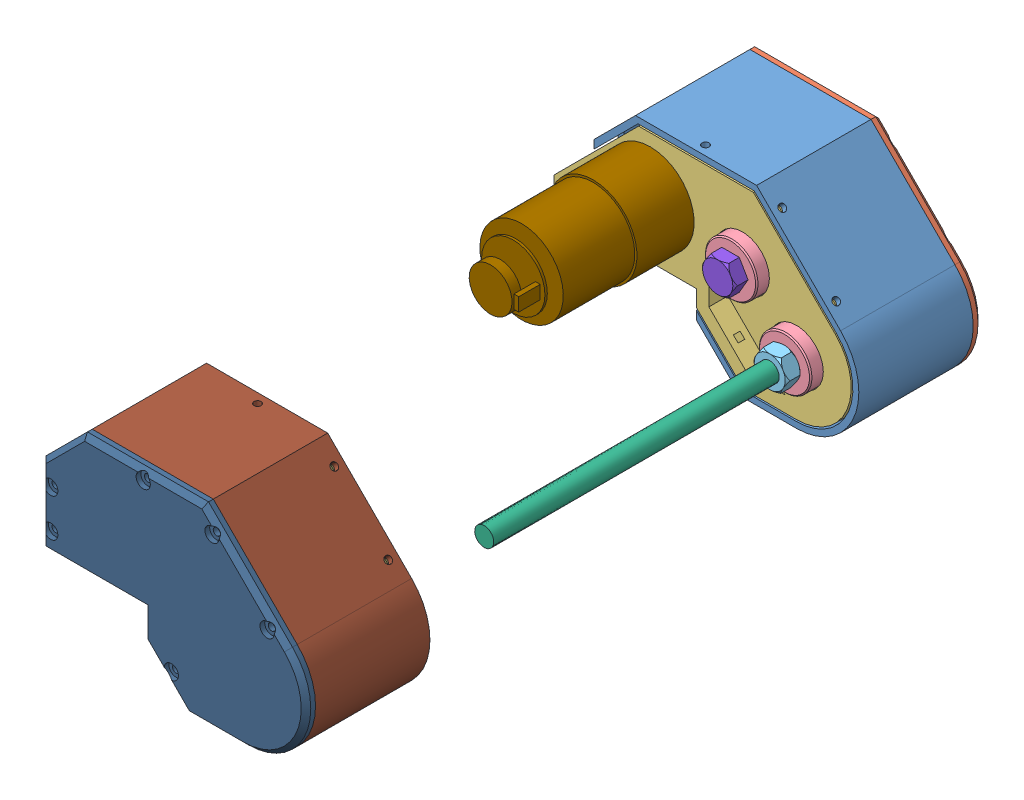
SolidWorks assembly 1_support_assembly, configuration Valor predeterminado. Lengths in mm.
Overall size (127.9 79.95 283.98).
20 component instances, 14 part files, 39 mates.
Components (placement in the parent):
- motorPlate-case-1: motorPlate-case [Valor predeterminado] at (-65.1774 -10.6604 87.1) size (111.1 79.95 48)
- motorPlate-lid-1: motorPlate-lid [Valor predeterminado] at (-65.1774 -10.6604 87.1) size (111.1 79.95 4)
- motorPlate-1: motorPlate [Valor predeterminado] at (-65.1774 -10.6604 127.1) size (124.7 73.55 8)
- bearing-1: bearing [Valor predeterminado] at (16.5226 -14.2604 122.1) size (22 22 7)
- nut-1: nut [Valor predeterminado] at (16.5226 -14.2604 115.9) size (16.51 13 6.2)
- threaded_rod-2: threaded_rod [Valor predeterminado] at (16.5226 -14.2604 90.1) x (0.592807 -0.805345 0) z (0 0 1) size (8 8 176)
- rod_gear_big_simple-1: rod_gear_big_simple [Valor predeterminado] at (16.5226 -14.2604 105.3824) x (0.982602 0.185725 0) z (0 0 -1) size (40.8 40.8 10)
- nut-2: nut [Valor predeterminado] at (16.5226 -14.2604 105.3824) size (16.51 13 6.2)
- nut-4: nut [Valor predeterminado] at (16.5226 -14.2604 140.1) x (0.999879 -0.015551 0) z (0 0 1) size (16.51 13 6.2)
- nut-5: nut [Valor predeterminado] at (16.5226 -14.2604 93.6824) size (16.51 13 6.2)
- bearing-2: bearing [Valor predeterminado] at (-6.1048 8.367 133.1) size (22 22 7)
- bearing-3: bearing [Valor predeterminado] at (-6.1048 8.367 122.1) size (22 22 7)
- bearing-4: bearing [Valor predeterminado] at (16.5226 -14.2604 133.1) size (22 22 7)
- bolt-1: bolt [Valor predeterminado] at (-6.1048 8.367 145.5) x (1 0 0) z (0 0 -1) size (16.13 12.7 55.4)
- motor_pololu-1: motor_pololu [Valor predeterminado] at (-44.7934 12.8206 135.1) x (0 -1 0) z (0 0 1) size (36.8 36.8 89)
- motorPlate-board_lid-1: motorPlate-board_lid [Valor predeterminado] at (-65.1774 -10.6604 363.0779) size (111.1 79.95 4)
- motorPlate-board_case-2: motorPlate-board_case [Valor predeterminado] at (-65.1774 -10.6604 267.0779) size (111.1 79.95 48)
- motorPlate-board-1: motorPlate-board [Valor predeterminado] at (-65.1774 -10.6604 315.0779) size (124.7 73.55 8)
- motor_gear_simple-1: motor_gear_simple [Valor predeterminado] at (-37.7934 12.8206 108.3824) x (0.999999 -0.00117 0) z (0 0 1) size (30 30 17)
- reduction_gear_simple-1: reduction_gear_simple [Valor predeterminado] at (-6.1048 8.367 108.3824) x (0.996288 -0.086078 0) z (0 0 1) size (40.8 40.8 23)
Mates (geometry in assembly coordinates):
- Coincidente5: coincident aligned: line of motorPlate-case-1 through (-0.174 39.4886 87.1) axis (-1 0 0); line of motorPlate-lid-1 through (-0.174 39.4886 87.1) axis (-1 0 0)
- Coincidente6: coincident aligned: line of motorPlate-case-1 through (-68.3774 22.107 87.1) axis (0 -1 0); line of motorPlate-lid-1 through (-68.3774 22.107 87.1) axis (0 -1 0)
- Concêntrico1: concentric aligned: circle of motorPlate-case-1; circle of motorPlate-1
- Coincidente8: coincident anti-aligned: plane of motorPlate-1 through (16.5226 -14.2604 129.1) normal (0 0 -1); plane of bearing-1 through (16.5226 -14.2604 129.1) normal (0 0 1)
- Concêntrico7: concentric anti-aligned: circle of motorPlate-1; circle of bearing-1
- Coincidente9: coincident anti-aligned: plane of bearing-1 through (16.5226 -14.2604 122.1) normal (0 0 -1); plane of nut-1 through (16.5226 -14.2604 122.1) normal (0 0 1)
- Concêntrico8: concentric aligned: circle of bearing-1; circle of nut-1
- Concêntrico9: concentric anti-aligned: circle of threaded_rod-2; circle of rod_gear_big_simple-1
- Coincidente12: coincident anti-aligned: plane of rod_gear_big_simple-1 through (16.5226 -14.2604 105.3824) normal (0 0 1); plane of nut-2 through (16.5226 -14.2604 105.3824) normal (0 0 -1)
- Concêntrico10: concentric anti-aligned: circle of rod_gear_big_simple-1; circle of nut-2
- Concêntrico11: concentric aligned: circle of threaded_rod-2; circle of nut-2
- Coincidente14: coincident anti-aligned: plane of rod_gear_big_simple-1 through (16.5226 -14.2604 99.8824) normal (0 0 -1); plane of nut-5 through (16.5226 -14.2604 99.8824) normal (0 0 1)
- Concêntrico12: concentric anti-aligned: circle of rod_gear_big_simple-1; circle of nut-5
- Coincidente15: coincident anti-aligned: plane of motorPlate-1 through (-6.1048 8.367 133.1) normal (0 0 1); plane of bearing-2 through (-6.1048 8.367 133.1) normal (0 0 -1)
- Concêntrico14: concentric aligned: circle of motorPlate-1; circle of bearing-3
- Coincidente16: coincident anti-aligned: plane of motorPlate-1 through (-6.1048 8.367 129.1) normal (0 0 -1); plane of bearing-3 through (-6.1048 8.367 129.1) normal (0 0 1)
- Coincidente17: coincident anti-aligned: plane of motorPlate-1 through (16.5226 -14.2604 133.1) normal (0 0 1); plane of bearing-4 through (16.5226 -14.2604 133.1) normal (0 0 -1)
- Coincidente18: coincident anti-aligned: plane of bearing-2 through (-6.1048 8.367 140.1) normal (0 0 1); plane of bolt-1 through (-6.1048 8.367 140.1) normal (0 0 -1)
- Concêntrico17: concentric anti-aligned: circle of bearing-2; circle of bolt-1
- Coincidente20: coincident anti-aligned: plane of motorPlate-1 through (16.5226 -14.2604 135.1) normal (0 0 1); plane of motor_pololu-1 through (-44.7934 12.8206 135.1) normal (0 0 -1)
- Concêntrico33: concentric aligned: circle of threaded_rod-2; circle of nut-4
- Coincidente23: coincident anti-aligned: plane of nut-4 through (16.5226 -14.2604 140.1) normal (0 0 -1); plane of bearing-4 through (16.5226 -14.2604 140.1) normal (0 0 1)
- Concêntrico36: concentric anti-aligned: circle of motorPlate-1; circle of motor_pololu-1
- Paralelo1: parallel aligned: line of motorPlate-1 through (-5.7322 -37.2604 135.1) axis (1 0 0); line of motorPlate-board-1 through (-5.7322 -37.2604 323.0779) axis (1 0 0)
- Paralelo2: parallel aligned: line of motorPlate-1 through (-85.1774 0.7815 135.1) axis (0 -1 0); line of motorPlate-board-1 through (-85.1774 0.7815 323.0779) axis (0 -1 0)
- Coincidente28: coincident aligned: line of motorPlate-board_lid-1 through (-0.174 39.4886 363.0779) axis (-1 0 0); line of motorPlate-board_case-2 through (-0.174 39.4886 363.0779) axis (-1 0 0)
- Coincidente29: coincident aligned: line of motorPlate-board_lid-1 through (-50.9958 39.4886 363.0779) axis (-0.707107 -0.707107 0); line of motorPlate-board_case-2 through (-50.9958 39.4886 363.0779) axis (-0.707107 -0.707107 0)
- Paralelo3: parallel aligned: line of motorPlate-board_case-2 through (-1.2095 36.9886 315.0779) axis (-1 0 0); line of motorPlate-board-1 through (-1.4995 36.2886 315.0779) axis (-1 0 0)
- Concêntrico38: concentric aligned: circle of motorPlate-board_case-2; circle of motorPlate-board-1
- Coincidente31: coincident aligned: plane of motorPlate-board_case-2 through (16.5226 -14.2604 315.0779) normal (0 0 -1); plane of motorPlate-board-1 through (16.5226 -14.2604 315.0779) normal (0 0 -1)
- Concêntrico39: concentric aligned: circle of bearing-1; circle of bearing-4
- Concêntrico40: concentric aligned: circle of threaded_rod-2; circle of bearing-4
- Concêntrico41: concentric anti-aligned: circle of motor_pololu-1; circle of motor_gear_simple-1
- Concêntrico42: concentric aligned: circle of bolt-1; circle of reduction_gear_simple-1
- Concêntrico43: concentric anti-aligned: circle of bearing-3; circle of bolt-1
- Coincidente35: coincident aligned: plane of rod_gear_big_simple-1 through (16.5226 -14.2604 95.3824) normal (0 0 -1); plane of reduction_gear_simple-1 through (-6.1048 8.367 95.3824) normal (0 0 -1)
- Coincidente36: coincident aligned: plane of motor_gear_simple-1 through (-37.7934 12.8206 108.3824) normal (0 0 -1); plane of reduction_gear_simple-1 through (-6.1048 8.367 108.3824) normal (0 0 -1)
- Coincidente37: coincident aligned: plane of threaded_rod-2 through (16.5226 -14.2604 90.1) normal (0 0 -1); plane of bolt-1 through (-6.1048 8.367 90.1) normal (0 0 -1)
- Coincidente38: coincident aligned: plane of motorPlate-case-1 through (16.5226 -14.2604 135.1) normal (0 0 1); plane of motorPlate-1 through (16.5226 -14.2604 135.1) normal (0 0 1)
